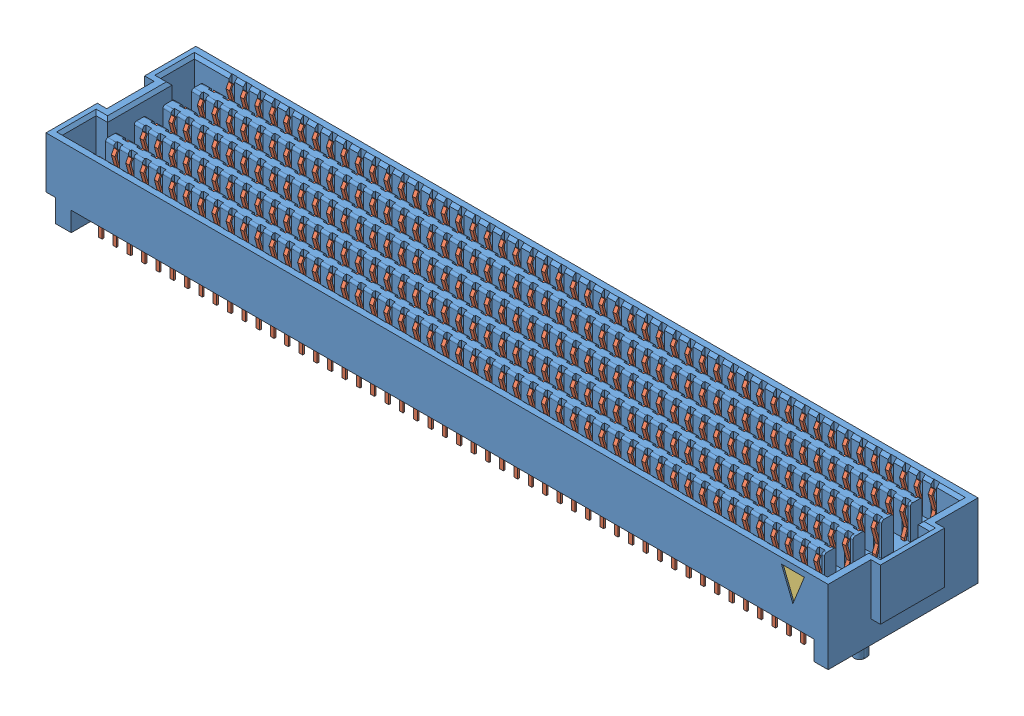
SolidWorks assembly SEAF_50_06_5_L_10_2_A_K_TR, configuration Default. Lengths in mm.
Overall size (70.15 7.82 13.28).
4 component instances, 4 part files, 0 mates.
Components (placement in the parent):
- _SEAF_50_06_5_L_10_1_A_0_K_TR_BODY_2_2-1: _SEAF_50_06_5_L_10_1_A_0_K_TR_BODY_2_2 [Default] at origin size (70.15 7.82 13.28)
- _SEAF_50_06_5_L_10_1_A_0_K_TR_cCON2_4-1: _SEAF_50_06_5_L_10_1_A_0_K_TR_cCON2_4 [Default] at origin size (62.55 6.17 13.03)
- _SEAF_10_K_PAD_6-1: _SEAF_10_K_PAD_6 [Default] at (0 4.699 0) (suppressed, hidden)
- _SEAF_TRIANGLE_FIRST_PIN_8-1: _SEAF_TRIANGLE_FIRST_PIN_8 [Default] at (31.115 1.27 6.3881) size (2.03 2.54 0.13)
